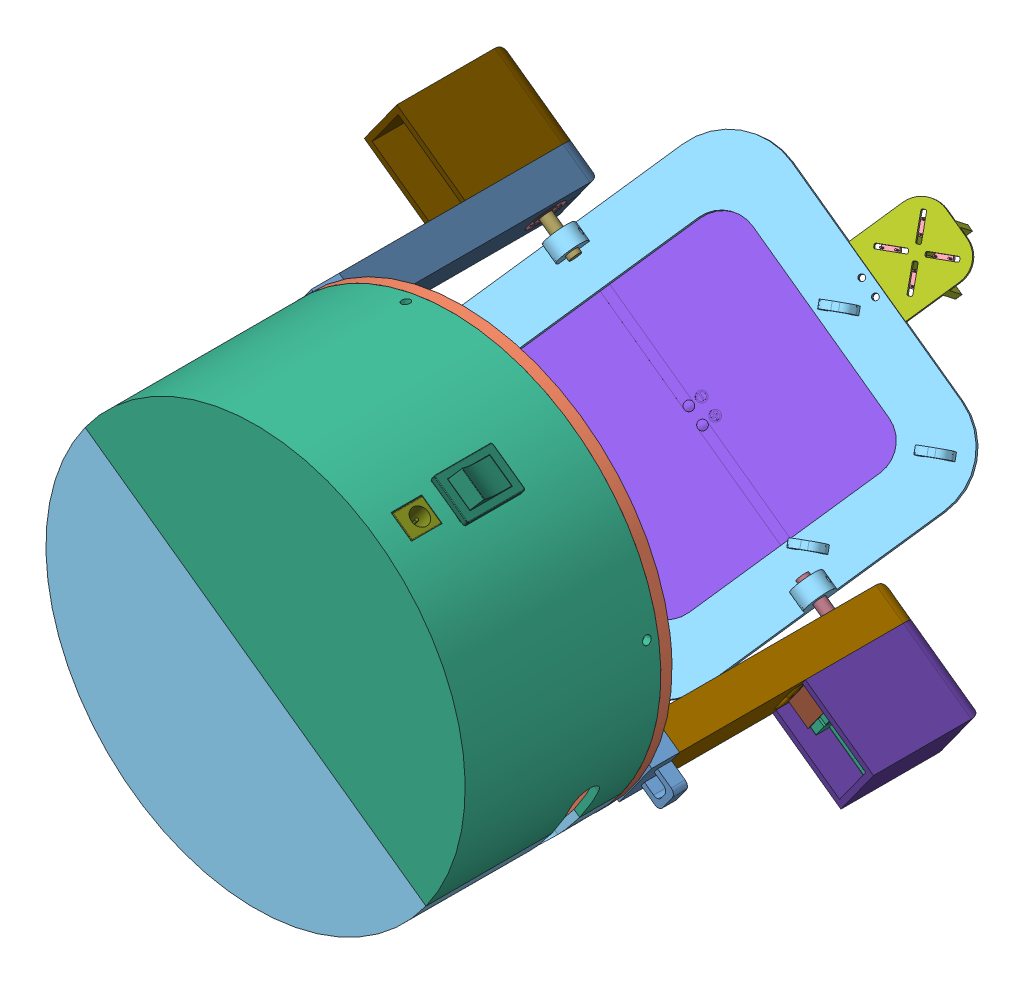
SolidWorks assembly zlozenie, configuration Domyślna. Lengths in mm.
Overall size (215.11 217.42 234.92).
30 component instances, 24 part files, 87 mates.
Components (placement in the parent):
- obrotnica-1: obrotnica [Domyślna] at (-46.3536 10.1701 35) x (-0.811945 0.583733 0) z (0 0 1) size (158 41.22 35)
- podstawa-1: podstawa [Domyślna] at (-46.3536 10.1701 60) x (0.080943 -0.996719 0) z (0.996719 0.080943 0) size (150 14 150)
- lozysko-25mm-1: lozysko-25mm [Default] at (-46.3536 10.1701 58) x (0 0 1) z (0.341039 -0.940049 0) size (12 47 47)
- lozysko-12mm-1: lozysko-12mm [Default] at (8.8587 -29.5238 -35) x (0.811945 -0.583733 0) z (-0.08402 -0.116868 0.989587) size (5 13 13)
- lozysko-12mm-2: lozysko-12mm [Default] at (-97.5061 46.9453 -35) x (0.811945 -0.583733 0) z (0.569575 0.792252 -0.21891) size (5 13 13)
- brama-1: brama [Domyślna] at (-116.1469 11.5947 5.4309) x (0.811945 -0.583733 0) z (-0.438518 -0.609957 -0.660041) size (115 115 11.05)
- serwo-sg-90-brama-1: serwo-sg-90-brama [Peça] at (27.6959 -43.0664 -29.85) x (0 0 1) z (-0.583733 -0.811945 0) size (32.1 29.95 12.4)
- czujnik-1: czujnik [Domyślna] at (-5.809 45.1518 -100.4012) x (-0.811945 0.583733 0) z (-0.438518 -0.609957 -0.660041) size (25 35 22)
- panel-fotowoltaiczny-1: panel-fotowoltaiczny [JZ135X85] at (-49.2793 6.1005 -40.7349) x (-0.811945 0.583733 0) z (-0.385288 -0.535917 0.75123) size (95 3.52 95)
- ramie_lewe-1: ramie_lewe [Domyślna] at (9.6707 -30.1075 -50) x (-0.811945 0.583733 0) z (0 0 1) size (12 20 85)
- ramie_prawe-2: ramie_prawe [Domyślna] at (-102.3778 50.4477 -50) x (0.811945 -0.583733 0) z (0 0 1) size (12 20 85)
- mocowanie-1: mocowanie [Domyślna] at (21.4845 -38.6008 -15.8) x (-0.583733 -0.811945 0) z (-0.811945 0.583733 0) size (12 5 8.55)
- mocowanie-2: mocowanie [Domyślna] at (21.4845 -38.6008 -43.6) x (-0.583733 -0.811945 0) z (-0.811945 0.583733 0) size (12 5 8.55)
- walek_prawy-1: walek_prawy [Domyślna] at (-103.1897 51.0314 -35) x (0.385288 0.535917 -0.75123) z (0.811945 -0.583733 0) size (7 7 20)
- walek_lewy-1: walek_lewy [Domyślna] at (13.7304 -33.0262 -35) x (0.385288 0.535917 -0.75123) z (-0.811945 0.583733 0) size (7 7 24)
- woltomierz-1: woltomierz [Domyślna] at (-95.8065 -58.9632 84.068) x (-0.81299 0.582278 0) z (-0.582278 -0.81299 0) size (47.8 28.8 40.1)
- przelacznik-1: przelacznik [Domyślna] at (-8.2292 75.1168 74.6982) x (0 0 1) z (-0.81299 0.582278 0) size (21.33 24.14 14.86)
- konektor-zasilania-1: konektor-zasilania [Domyślna] at (-2.5852 71.0745 111.3) x (0.81299 -0.582278 0) z (0.582278 0.81299 0) size (8.98 14.58 14.04)
- osłona_lewa-1: osłona_lewa [Domyślna] at (26.7215 -42.3659 -50) x (-0.583733 -0.811945 0) z (0 0 1) size (20 30 40)
- oslona_prawa-1: oslona_prawa [Domyślna] at (-119.4286 62.7061 -50) x (0.583733 0.811945 0) z (0 0 1) size (20 30 40)
- mocowanie-3: mocowanie [Domyślna] at (-114.1916 58.941 -44) x (0.583733 0.811945 0) z (0.811945 -0.583733 0) size (12 5 8.55)
- serwo-hd-1160A-obrotnica-1: serwo-hd-1160A-obrotnica [Varsayılan] at (-36.7967 12.1864 105.4) x (-0.581782 -0.813345 0) z (0.813345 -0.581782 0) size (40.1 33.2 13.2)
- mocowanie-serwo-obrotnica-2: mocowanie-serwo-obrotnica [Domyślna] at (-61.9453 -11.6276 88) x (0.581782 0.813345 0) z (0 0 -1) size (22 13 28)
- mocowanie-serwo-obrotnica-dluzsze-1: mocowanie-serwo-obrotnica-dluzsze [Domyślna] at (-38.0923 21.7196 88) x (-0.581782 -0.813345 0) z (0 0 -1) size (28 13 28)
- fotorezystor-1: fotorezystor [Domyślna] at (-27.6712 44.6531 -88.4456) x (0.301692 -0.791713 0.5312) z (-0.438518 -0.609957 -0.660041) size (4.2 5 6.6)
- fotorezystor-2: fotorezystor [Domyślna] at (-19.5139 39.2484 -88.8706) x (-0.846572 0.033811 0.5312) z (-0.438518 -0.609957 -0.660041) size (4.2 5 6.6)
- fotorezystor-3: fotorezystor [Domyślna] at (-15.9644 44.1855 -95.7913) x (-0.301692 0.791713 -0.5312) z (-0.438518 -0.609957 -0.660041) size (4.2 5 6.6)
- fotorezystor-4: fotorezystor [Domyślna] at (-23.535 49.8007 -95.9507) x (0.846572 -0.033811 -0.5312) z (-0.438518 -0.609957 -0.660041) size (4.2 5 6.6)
- oslona_elektroniki_1-1: oslona_elektroniki_1 [Domyślna] at (-46.3536 10.1701 120) x (0.81299 -0.582278 0) z (0 0 -1) size (150 85 70)
- oslona_elektroniki_2-1: oslona_elektroniki_2 [Domyślna] at (-46.3536 10.1701 120) x (0.81299 -0.582278 0) z (0 0 -1) size (150 75 70)
Mates (geometry in assembly coordinates):
- Koncentryczne3: concentric anti-aligned: cylinder of obrotnica-1 through (-46.3536 10.1701 70) axis (0 0 -1) radius 12.5; cylinder of lozysko-25mm-1 through (-46.3536 10.1701 58) axis (0 0 1) radius 12.5
- Wspólnie9: coincident anti-aligned: plane of obrotnica-1 through (-46.3536 10.1701 46) normal (0 0 1); plane of lozysko-25mm-1 through (-58.8562 5.6343 46) normal (0 0 -1)
- Koncentryczne4: concentric anti-aligned: cylinder of podstawa-1 through (-46.3536 10.1701 58) axis (0 0 -1) radius 23.5; cylinder of lozysko-25mm-1 through (-46.3536 10.1701 58) axis (0 0 1) radius 23.5
- Wspólnie10: coincident anti-aligned: plane of podstawa-1 through (-46.3536 10.1701 58) normal (0 0 -1); plane of lozysko-25mm-1 through (-64.8725 3.4516 58) normal (0 0 1)
- Koncentryczne13: concentric aligned: cylinder of lozysko-12mm-1 through (8.8587 -29.5238 -35) axis (0.811945 -0.583733 0) radius 2; cylinder of brama-1 through (-93.0404 43.7348 -35) axis (0.811945 -0.583733 0) radius 2.1
- Koncentryczne21: concentric aligned: cylinder of brama-1 through (-25.4814 44.3416 -74.4621) axis (-0.438518 -0.609957 -0.660041) radius 1; cylinder of czujnik-1 through (-29.4281 38.852 -80.4025) axis (-0.438518 -0.609957 -0.660041) radius 1
- Koncentryczne22: concentric aligned: cylinder of brama-1 through (-20.6097 40.8392 -74.4621) axis (-0.438518 -0.609957 -0.660041) radius 1; cylinder of czujnik-1 through (-24.5564 35.3496 -80.4025) axis (-0.438518 -0.609957 -0.660041) radius 1
- Wspólnie18: coincident anti-aligned: plane of brama-1 through (-117.024 10.3748 4.1109) normal (-0.438518 -0.609957 -0.660041); plane of czujnik-1 through (-6.2475 44.5419 -101.0613) normal (0.438518 0.609957 0.660041)
- Wspólnie19: coincident anti-aligned: plane of brama-1 through (-117.4625 9.7648 3.4508) normal (-0.438518 -0.609957 -0.660041); plane of panel-fotowoltaiczny-1 through (-48.6216 7.0154 -39.7449) normal (0.438518 0.609957 0.660041)
- Odległość3: distance = 10 mm aligned: plane of panel-fotowoltaiczny-1 through (-29.6709 -47.9979 -6.0416) normal (-0.385288 -0.535917 0.75123); plane of brama-1 through (-117.4625 9.7648 3.4508) normal (-0.385288 -0.535917 0.75123)
- Odległość4: distance = 10 mm aligned: plane of panel-fotowoltaiczny-1 through (-70.2034 58.3689 -77.4084) normal (-0.811945 0.583733 0); plane of brama-1 through (-117.4625 9.7648 3.4508) normal (-0.811945 0.583733 0)
- Koncentryczne25: concentric anti-aligned: cylinder of obrotnica-1 through (8.0204 -37.5423 45) axis (0 0 -1) radius 1.5; cylinder of ramie_lewe-1 through (8.0204 -37.5423 25) axis (0 0 1) radius 1.5
- Koncentryczne26: concentric anti-aligned: circle of obrotnica-1; cylinder of ramie_lewe-1 through (11.321 -22.6727 25) axis (0 0 1) radius 1.5
- Wspólnie22: coincident anti-aligned: plane of obrotnica-1 through (-46.3536 10.1701 35) normal (0 0 -1); plane of ramie_lewe-1 through (9.6707 -30.1075 35) normal (0 0 1)
- Koncentryczne27: concentric anti-aligned: cylinder of obrotnica-1 through (-108.8998 46.5153 45) axis (0 0 -1) radius 1.5; cylinder of ramie_prawe-2 through (-108.8998 46.5153 25) axis (0 0 1) radius 1.5
- Koncentryczne28: concentric anti-aligned: cylinder of obrotnica-1 through (-95.8558 54.3801 45) axis (0 0 -1) radius 1.5; cylinder of ramie_prawe-2 through (-95.8558 54.3801 25) axis (0 0 1) radius 1.5
- Wspólnie23: coincident anti-aligned: plane of obrotnica-1 through (-46.3536 10.1701 35) normal (0 0 -1); plane of ramie_prawe-2 through (-102.3778 50.4477 35) normal (0 0 1)
- Koncentryczne30: concentric aligned: cylinder of lozysko-12mm-2 through (-97.5061 46.9453 -35) axis (0.811945 -0.583733 0) radius 2; cylinder of brama-1 through (-93.0404 43.7348 -35) axis (0.811945 -0.583733 0) radius 2.1
- Odległość5: distance = 5.5 mm anti-aligned: plane of brama-1 through (-117.4625 9.7648 3.4508) normal (-0.811945 0.583733 0); plane of ramie_prawe-2 through (-103.3435 38.8258 35) normal (0.811945 -0.583733 0)
- Koncentryczne31: concentric aligned: cylinder of lozysko-12mm-2 through (-97.5061 46.9453 -35) axis (0.811945 -0.583733 0) radius 6.5; cylinder of ramie_prawe-2 through (-101.5658 49.864 -35) axis (0.811945 -0.583733 0) radius 6.5
- Wspólnie26: coincident anti-aligned: plane of lozysko-12mm-2 through (-102.199 48.9832 -39.8348) normal (-0.811945 0.583733 0); plane of ramie_prawe-2 through (-101.5658 49.864 -35) normal (0.811945 -0.583733 0)
- Koncentryczne32: concentric anti-aligned: cylinder of lozysko-12mm-1 through (8.8587 -29.5238 -35) axis (0.811945 -0.583733 0) radius 6.5; cylinder of ramie_lewe-1 through (8.8587 -29.5238 -35) axis (-0.811945 0.583733 0) radius 6.5
- Wspólnie27: coincident anti-aligned: plane of lozysko-12mm-1 through (11.721 -25.5425 -34.2868) normal (0.811945 -0.583733 0); plane of ramie_lewe-1 through (8.8587 -29.5238 -35) normal (-0.811945 0.583733 0)
- Równolegle1: parallel anti-aligned: plane of serwo-sg-90-brama-1 through (15.3891 -39.8841 -25.1) normal (-0.811945 0.583733 0); plane of ramie_lewe-1 through (20.3797 -25.4905 35) normal (0.811945 -0.583733 0)
- Koncentryczne33: concentric anti-aligned: cylinder of lozysko-12mm-1 through (8.8587 -29.5238 -35) axis (0.811945 -0.583733 0) radius 2; cylinder of serwo-sg-90-brama-1 through (12.0253 -31.8003 -35) axis (-0.811945 0.583733 0) radius 0.8
- Równolegle2: parallel aligned: plane of serwo-sg-90-brama-1 through (17.9237 -43.5537 -45.05) normal (-0.583733 -0.811945 0); plane of ramie_lewe-1 through (8.705 -41.7294 35) normal (-0.583733 -0.811945 0)
- Wspólnie30: coincident anti-aligned: plane of serwo-sg-90-brama-1 through (14.5423 -33.6099 -35) normal (-0.811945 0.583733 0); plane of ramie_lewe-1 through (20.3797 -25.4905 35) normal (0.811945 -0.583733 0)
- Koncentryczne34: concentric anti-aligned: cylinder of ramie_lewe-1 through (4.799 -26.6051 -43.75) axis (0.811945 -0.583733 0) radius 1.1; cylinder of mocowanie-2 through (21.4845 -38.6008 -43.75) axis (-0.811945 0.583733 0) radius 1.1
- Wspólnie31: coincident anti-aligned: plane of ramie_lewe-1 through (20.3797 -25.4905 35) normal (0.811945 -0.583733 0); plane of mocowanie-2 through (14.5423 -33.6099 -43.6) normal (-0.811945 0.583733 0)
- Równolegle4: parallel aligned: plane of serwo-sg-90-brama-1 through (18.4199 -42.8635 -45.9) normal (0 0 -1); plane of mocowanie-2 through (18.0447 -28.7382 -46.1) normal (0 0 -1)
- Koncentryczne35: concentric anti-aligned: cylinder of ramie_lewe-1 through (4.799 -26.6051 -15.95) axis (0.811945 -0.583733 0) radius 1.1; cylinder of mocowanie-1 through (21.4845 -38.6008 -15.95) axis (-0.811945 0.583733 0) radius 1.1
- Równolegle5: parallel aligned: plane of serwo-sg-90-brama-1 through (18.4199 -42.8635 -13.8) normal (0 0 1); plane of mocowanie-1 through (18.0447 -28.7382 -13.3) normal (0 0 1)
- Wspólnie35: coincident anti-aligned: plane of ramie_lewe-1 through (20.3797 -25.4905 35) normal (0.811945 -0.583733 0); plane of mocowanie-1 through (14.5423 -33.6099 -15.8) normal (-0.811945 0.583733 0)
- Koncentryczne36: concentric anti-aligned: cylinder of lozysko-12mm-2 through (-97.5061 46.9453 -35) axis (0.811945 -0.583733 0) radius 2; cylinder of walek_prawy-1 through (-86.9508 39.3568 -35) axis (-0.811945 0.583733 0) radius 2
- Wspólnie36: coincident anti-aligned: plane of lozysko-12mm-2 through (-101.8661 49.4463 -37.293) normal (-0.811945 0.583733 0); plane of walek_prawy-1 through (-101.5658 49.864 -35) normal (0.811945 -0.583733 0)
- Równolegle7: parallel aligned: cylinder of brama-1 through (-68.0652 73.3347 -78.9469) axis (-0.385288 -0.535917 0.75123) radius 1.1; cylinder of walek_prawy-1 through (-89.2561 43.8593 -37.6293) axis (-0.385288 -0.535917 0.75123) radius 1.1
- Koncentryczne41: concentric aligned: cylinder of lozysko-12mm-1 through (8.8587 -29.5238 -35) axis (0.811945 -0.583733 0) radius 2; cylinder of walek_lewy-1 through (-5.7563 -19.0166 -35) axis (0.811945 -0.583733 0) radius 2
- Wspólnie38: coincident anti-aligned: plane of lozysko-12mm-1 through (10.2162 -27.6356 -34.6618) normal (0.811945 -0.583733 0); plane of walek_lewy-1 through (8.8587 -29.5238 -35) normal (-0.811945 0.583733 0)
- Równolegle8: parallel aligned: cylinder of brama-1 through (-0.1761 -18.9638 -38.7561) axis (-0.385288 -0.535917 0.75123) radius 1.1; cylinder of walek_lewy-1 through (-0.754 -19.7677 -37.6293) axis (-0.385288 -0.535917 0.75123) radius 1.1
- Wspólnie44: coincident anti-aligned: plane of ramie_lewe-1 through (20.3797 -25.4905 35) normal (0.811945 -0.583733 0); plane of osłona_lewa-1 through (20.3797 -25.4905 -10) normal (-0.811945 0.583733 0)
- Równolegle9: parallel anti-aligned: plane of mocowanie-2 through (21.4845 -38.6008 -45.1) normal (0 0 -1); plane of osłona_lewa-1 through (26.7215 -42.3659 -45.5) normal (0 0 1)
- Wspólnie47: coincident aligned: plane of ramie_lewe-1 through (9.6707 -30.1075 -50) normal (0 0 -1); plane of osłona_lewa-1 through (26.7215 -42.3659 -50) normal (0 0 -1)
- Wspólnie48: coincident aligned: plane of ramie_lewe-1 through (8.705 -41.7294 35) normal (-0.583733 -0.811945 0); plane of osłona_lewa-1 through (8.705 -41.7294 -10) normal (-0.583733 -0.811945 0)
- Wspólnie49: coincident aligned: plane of ramie_prawe-2 through (-113.0868 45.8306 35) normal (-0.583733 -0.811945 0); plane of oslona_prawa-1 through (-113.0868 45.8306 -10) normal (-0.583733 -0.811945 0)
- Wspólnie50: coincident aligned: plane of ramie_prawe-2 through (-102.3778 50.4477 -50) normal (0 0 -1); plane of oslona_prawa-1 through (-119.4286 62.7061 -50) normal (0 0 -1)
- Wspólnie51: coincident anti-aligned: plane of ramie_prawe-2 through (-113.0868 45.8306 35) normal (-0.811945 0.583733 0); plane of oslona_prawa-1 through (-113.0868 45.8306 -10) normal (0.811945 -0.583733 0)
- Wspólnie53: coincident anti-aligned: plane of oslona_prawa-1 through (-119.4286 62.7061 -45.5) normal (0 0 1); plane of mocowanie-3 through (-114.1916 58.941 -45.5) normal (0 0 -1)
- Wspólnie54: coincident anti-aligned: plane of oslona_prawa-1 through (-107.8068 61.7404 -45.5) normal (-0.811945 0.583733 0); plane of mocowanie-3 through (-114.8116 51.9971 -45.5) normal (0.811945 -0.583733 0)
- Wspólnie55: coincident aligned: plane of oslona_prawa-1 through (-114.8116 51.9971 -45.5) normal (-0.583733 -0.811945 0); plane of mocowanie-3 through (-110.7519 49.0784 -46.5) normal (-0.583733 -0.811945 0)
- Koncentryczne43: concentric anti-aligned: cylinder of obrotnica-1 through (-46.3536 10.1701 70) axis (0 0 -1) radius 12.5; cylinder of serwo-hd-1160A-obrotnica-1 through (-46.3536 10.1701 72.2) axis (0 0 1) radius 2.8
- Koncentryczne45: concentric anti-aligned: cylinder of serwo-hd-1160A-obrotnica-1 through (-60.4036 -9.4722 86.3) axis (0 0 -1) radius 2.25; cylinder of mocowanie-serwo-obrotnica-2 through (-60.4036 -9.4722 86) axis (0 0 1) radius 2.25
- Wspólnie63: coincident anti-aligned: plane of serwo-hd-1160A-obrotnica-1 through (-56.5772 -15.4673 86) normal (0 0 1); plane of mocowanie-serwo-obrotnica-2 through (-61.9453 -11.6276 86) normal (0 0 -1)
- Równolegle16: parallel aligned: plane of serwo-hd-1160A-obrotnica-1 through (-47.5328 19.8659 78.6) normal (-0.813345 0.581782 0); plane of mocowanie-serwo-obrotnica-2 through (-70.7227 -12.726 86) normal (-0.813345 0.581782 0)
- Koncentryczne46: concentric anti-aligned: cylinder of serwo-hd-1160A-obrotnica-1 through (-40.2158 18.7509 86.3) axis (0 0 -1) radius 2.25; cylinder of mocowanie-serwo-obrotnica-dluzsze-1 through (-40.2158 18.7509 86) axis (0 0 1) radius 2.25
- Równolegle17: parallel aligned: plane of serwo-hd-1160A-obrotnica-1 through (-36.7967 12.1864 78.6) normal (0.813345 -0.581782 0); plane of mocowanie-serwo-obrotnica-dluzsze-1 through (-28.733 23.6314 86) normal (0.813345 -0.581782 0)
- Wspólnie65: coincident anti-aligned: plane of serwo-hd-1160A-obrotnica-1 through (-44.0421 24.746 86) normal (0 0 1); plane of mocowanie-serwo-obrotnica-dluzsze-1 through (-38.0923 21.7196 86) normal (0 0 -1)
- Wspólnie66: coincident anti-aligned: plane of podstawa-1 through (-46.3536 10.1701 60) normal (0 0 1); plane of mocowanie-serwo-obrotnica-dluzsze-1 through (-38.0923 21.7196 60) normal (0 0 -1)
- Wspólnie70: coincident anti-aligned: plane of czujnik-1 through (-6.686 43.9319 -101.7213) normal (-0.438518 -0.609957 -0.660041); plane of fotorezystor-3 through (-15.9644 44.1855 -95.7913) normal (0.438518 0.609957 0.660041)
- Równolegle19: parallel anti-aligned: plane of czujnik-1 through (-11.2752 57.2494 -80.6782) normal (0.301692 -0.791713 0.5312); plane of fotorezystor-3 through (-17.7463 45.894 -96.1863) normal (-0.301692 0.791713 -0.5312)
- Odległość10: distance = 2 mm: cylinder of fotorezystor-3 through (-15.9644 44.1855 -95.7913) axis (-0.438518 -0.609957 -0.660041) radius 2.5; line of czujnik-1 through (-12.2755 44.3501 -98.3942) axis (0.301692 -0.791713 0.5312)
- Wspólnie75: coincident anti-aligned: plane of czujnik-1 through (-6.686 43.9319 -101.7213) normal (-0.438518 -0.609957 -0.660041); plane of fotorezystor-4 through (-23.535 49.8007 -95.9507) normal (0.438518 0.609957 0.660041)
- Równolegle21: parallel aligned: plane of czujnik-1 through (-14.1689 58.4675 -79.8814) normal (0.846572 -0.033811 -0.5312); plane of fotorezystor-4 through (-22.1664 50.8036 -97.7867) normal (0.846572 -0.033811 -0.5312)
- Odległość11: distance = 1.5 mm anti-aligned: plane of fotorezystor-3 through (-14.1825 42.4771 -95.3963) normal (0.301692 -0.791713 0.5312); plane of czujnik-1 through (-10.8226 56.0618 -79.8814) normal (-0.301692 0.791713 -0.5312)
- Odległość12: distance = 1.5 mm anti-aligned: plane of fotorezystor-4 through (-22.1664 50.8036 -97.7867) normal (0.846572 -0.033811 -0.5312); plane of czujnik-1 through (-12.8991 58.4168 -80.6782) normal (-0.846572 0.033811 0.5312)
- Odległość13: distance = 2 mm: cylinder of fotorezystor-4 through (-23.535 49.8007 -95.9507) axis (-0.438518 -0.609957 -0.660041) radius 2.5; line of czujnik-1 through (-25.2312 53.3769 -98.1286) axis (0.846572 -0.033811 -0.5312)
- Wspólnie81: coincident anti-aligned: plane of czujnik-1 through (-6.686 43.9319 -101.7213) normal (-0.438518 -0.609957 -0.660041); plane of fotorezystor-1 through (-27.6712 44.6531 -88.4456) normal (0.438518 0.609957 0.660041)
- Równolegle23: parallel anti-aligned: plane of czujnik-1 through (-14.9395 57.3957 -78.3789) normal (0.301692 -0.791713 0.5312); plane of fotorezystor-1 through (-29.4531 46.3615 -88.8406) normal (-0.301692 0.791713 -0.5312)
- Odległość14: distance = 1.5 mm anti-aligned: plane of fotorezystor-1 through (-25.8893 42.9446 -88.0507) normal (0.301692 -0.791713 0.5312); plane of czujnik-1 through (-14.487 56.2081 -77.5821) normal (-0.301692 0.791713 -0.5312)
- Odległość15: distance = 4 mm: cylinder of fotorezystor-1 through (-27.6712 44.6531 -88.4456) axis (-0.438518 -0.609957 -0.660041) radius 2.5; plane of czujnik-1 through (-22.5586 57.7 -73.5981) normal (0.846572 -0.033811 -0.5312)
- Wspólnie83: coincident anti-aligned: plane of czujnik-1 through (-6.686 43.9319 -101.7213) normal (-0.438518 -0.609957 -0.660041); plane of fotorezystor-2 through (-19.5139 39.2484 -88.8706) normal (0.438518 0.609957 0.660041)
- Równolegle27: parallel anti-aligned: plane of czujnik-1 through (-12.8631 55.0407 -77.5821) normal (0.846572 -0.033811 -0.5312); plane of fotorezystor-2 through (-20.8825 38.2455 -87.0345) normal (-0.846572 0.033811 0.5312)
- Odległość17: distance = 2 mm: cylinder of fotorezystor-2 through (-19.5139 39.2484 -88.8706) axis (-0.438518 -0.609957 -0.660041) radius 2.5; line of czujnik-1 through (-18.0716 35.6823 -86.5333) axis (-0.846572 0.033811 0.5312)
- Odległość19: distance = 1.5 mm anti-aligned: plane of fotorezystor-2 through (-18.1453 40.2513 -90.7067) normal (0.846572 -0.033811 -0.5312); plane of czujnik-1 through (-11.5932 54.99 -78.3789) normal (-0.846572 0.033811 0.5312)
- Koncentryczne47: concentric aligned: cylinder of podstawa-1 through (-46.3536 10.1701 50) axis (0 0 1) radius 72.5; cylinder of oslona_elektroniki_1-1 through (-46.3536 10.1701 50) axis (0 0 1) radius 72.5
- Wspólnie85: coincident anti-aligned: plane of podstawa-1 through (-46.3536 10.1701 50) normal (0 0 1); plane of oslona_elektroniki_1-1 through (-46.3536 10.1701 50) normal (0 0 -1)
- Wspólnie86: coincident anti-aligned: plane of woltomierz-1 through (-66.1719 -56.5715 71.218) normal (0.81299 -0.582278 0); plane of oslona_elektroniki_1-1 through (-59.8833 -47.7912 97.718) normal (-0.81299 0.582278 0)
- Wspólnie87: coincident anti-aligned: plane of woltomierz-1 through (-103.0817 -30.1361 71.218) normal (0 0 -1); plane of oslona_elektroniki_1-1 through (-96.8744 -21.2975 71.218) normal (0 0 1)
- Wspólnie88: coincident anti-aligned: plane of woltomierz-1 through (-95.8065 -58.9632 84.068) normal (0.582278 0.81299 0); plane of oslona_elektroniki_1-1 through (-95.8472 -58.9341 120) normal (-0.582278 -0.81299 0)
- Koncentryczne48: concentric aligned: cylinder of podstawa-1 through (-46.3536 10.1701 50) axis (0 0 1) radius 72.5; cylinder of oslona_elektroniki_2-1 through (-46.3536 10.1701 50) axis (0 0 1) radius 72.5
- Wspólnie89: coincident anti-aligned: plane of podstawa-1 through (-46.3536 10.1701 50) normal (0 0 1); plane of oslona_elektroniki_2-1 through (-46.3536 10.1701 50) normal (0 0 -1)
- Wspólnie91: coincident anti-aligned: plane of oslona_elektroniki_1-1 through (-46.3536 10.1701 120) normal (0.582278 0.81299 0); plane of oslona_elektroniki_2-1 through (-46.3536 10.1701 120) normal (-0.582278 -0.81299 0)
- Wspólnie92: coincident anti-aligned: plane of przelacznik-1 through (-3.6914 58.573 76.4953) normal (0.81299 -0.582278 0); plane of oslona_elektroniki_2-1 through (-32.335 18.5801 95.5) normal (-0.81299 0.582278 0)
- Odległość20: distance = 1.5 mm anti-aligned: plane of przelacznik-1 through (-11.9049 67.3456 76) normal (0 0 -1); plane of oslona_elektroniki_2-1 through (-42.9038 26.1497 74.5) normal (0 0 1)
- Stycznie2: tangent anti-aligned: plane of przelacznik-1 through (-8.2292 75.1168 74.6982) normal (-0.582278 -0.81299 0); cylinder of oslona_elektroniki_2-1 through (-46.3536 10.1701 50) axis (0 0 1) radius 75
- Wspólnie94: coincident anti-aligned: plane of konektor-zasilania-1 through (0.9757 68.5241 100.5) normal (0.81299 -0.582278 0); plane of oslona_elektroniki_2-1 through (-33.9609 19.7447 100.5) normal (-0.81299 0.582278 0)
- Stycznie3: tangent aligned: plane of konektor-zasilania-1 through (-2.5852 71.0745 105.9) normal (0.582278 0.81299 0); cylinder of oslona_elektroniki_2-1 through (-46.3536 10.1701 50) axis (0 0 1) radius 75
- Wspólnie95: coincident anti-aligned: plane of konektor-zasilania-1 through (-6.1461 73.6248 100.5) normal (0 0 -1); plane of oslona_elektroniki_2-1 through (-41.2778 24.9852 100.5) normal (0 0 1)
